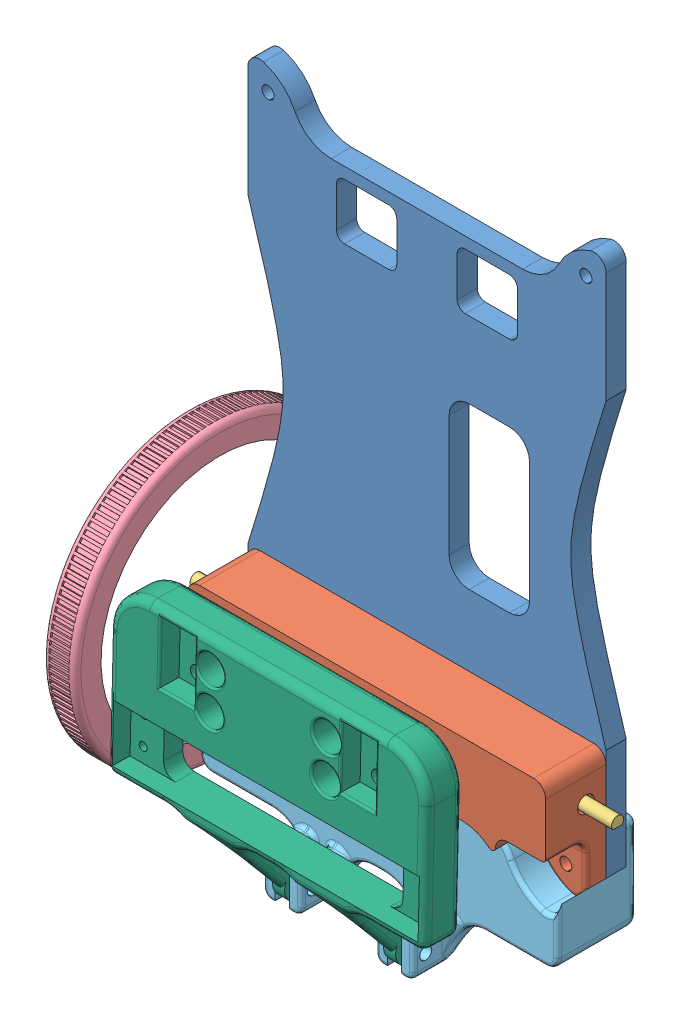
SolidWorks assembly Montagem, configuration Valor predeterminado. Lengths in mm.
Overall size (106.87 163.58 97.49).
9 component instances, 7 part files, 17 mates.
Components (placement in the parent):
- chassi-1: chassi [Valor predeterminado] at (23.4572 -41.9098 -2.5) size (89 136.28 5)
- suporte motor-1: suporte motor [Valor predeterminado] at (7.3294 33.688 2.5) x (-1 0 0) z (0 0 1) size (89 30.54 15)
- Pololu #2218 Micro Metal Gearmotor HP-1: Pololu #2218 Micro Metal Gearmotor HP [Valor predeterminado] at (48.8933 -50.8109 7.5) x (0 0 -1) z (-1 0 0) size (10 12 35.52)
- Pololu #2218 Micro Metal Gearmotor HP-2: Pololu #2218 Micro Metal Gearmotor HP [Valor predeterminado] at (-18.1067 -50.8109 7.5) x (0 0 1) z (1 0 0) size (10 12 35.52)
- Roda-70mm-1: Roda-70mm [Valor predeterminado] at (-31.1067 -50.8109 7.5) x (0 0.476407 0.879225) z (-1 0 0) size (71.92 71.92 8)
  - pololu wheel 70x8mm ref.14251-1: pololu wheel 70x8mm ref.14251 [Valor predeterminado] at origin (suppressed, hidden)
  - pololu wheel 70x8mm ref.14252-1: pololu wheel 70x8mm ref.14252 [Valor predeterminado] at origin size (71.92 71.92 8)
- SuporteDoArraynovonovonew-1: SuporteDoArraynovonovonew [Valor predeterminado] at (-0.7051 -59.7752 -2.5) x (0 0 1) z (1 0 0) size (30 34.04 89)
- Peça5-1: Peça5 [Valor predeterminado] at (3.0133 -87.9126 20.0486) x (0 0.999717 -0.023778) z (-1 0 0) size (65 25.86 78.95)
Mates (geometry in assembly coordinates):
- Concêntrico3: concentric aligned: circle of suporte motor-1; circle of Pololu #2218 Micro Metal Gearmotor HP-2
- Coincidente3: coincident anti-aligned: plane of suporte motor-1 through (-27.1067 -55.9109 12.6) normal (1 0 0); plane of Pololu #2218 Micro Metal Gearmotor HP-2 through (-27.1067 -54.6609 4.65) normal (-1 0 0)
- Concêntrico4: concentric aligned: circle of suporte motor-1; circle of Pololu #2218 Micro Metal Gearmotor HP-1
- Coincidente4: coincident anti-aligned: plane of suporte motor-1 through (57.8933 -55.9109 12.6) normal (-1 0 0); plane of Pololu #2218 Micro Metal Gearmotor HP-1 through (57.8933 -54.6609 10.35) normal (1 0 0)
- Coincidente5: coincident anti-aligned: plane of chassi-1 through (51.1131 -4.1109 2.5) normal (0 0 1); plane of suporte motor-1 through (56.8933 -44.7109 2.5) normal (0 0 -1)
- Concêntrico5: concentric aligned: circle of chassi-1; circle of suporte motor-1
- Concêntrico6: concentric aligned: circle of chassi-1; circle of suporte motor-1
- Concêntrico7: concentric anti-aligned: circle of Pololu #2218 Micro Metal Gearmotor HP-2; circle of Roda-70mm-1/pololu wheel 70x8mm ref.14252-1
- Distância1: distance = 2 mm anti-aligned: plane of Roda-70mm-1/pololu wheel 70x8mm ref.14252-1 through (-31.1067 -65.3012 54.5538) normal (1 0 0); plane of suporte motor-1 through (-29.1067 -69.2503 17.5) normal (-1 0 0)
- Coincidente10: coincident anti-aligned: plane of chassi-1 through (51.1131 -4.1109 -2.5) normal (0 0 -1); plane of SuporteDoArraynovonovonew-1 through (56.8933 -43.0021 -2.5) normal (0 0 1)
- Concêntrico8: concentric aligned: circle of chassi-1; circle of SuporteDoArraynovonovonew-1
- Concêntrico9: concentric aligned: circle of suporte motor-1; circle of SuporteDoArraynovonovonew-1
- Distância2: distance = 0.01 mm: plane of Peça5-1 through (-0.2967 -68.7096 19.8239) normal (-1 0 0); plane of SuporteDoArraynovonovonew-1 through (-0.3067 -63.7521 27.5) normal (1 0 0)
- Concêntrico10: concentric: circle of SuporteDoArraynovonovonew-1; circle of Peça5-1
- Concêntrico11: concentric: circle of SuporteDoArraynovonovonew-1; circle of Peça5-1
- Concêntrico12: concentric anti-aligned: circle of SuporteDoArraynovonovonew-1; circle of Peça5-1
- Coincidente11: coincident anti-aligned: plane of SuporteDoArraynovonovonew-1 through (27.5933 -91.7521 -2.5) normal (1 0 0); plane of Peça5-1 through (27.5933 -87.9126 20.0486) normal (-1 0 0)
